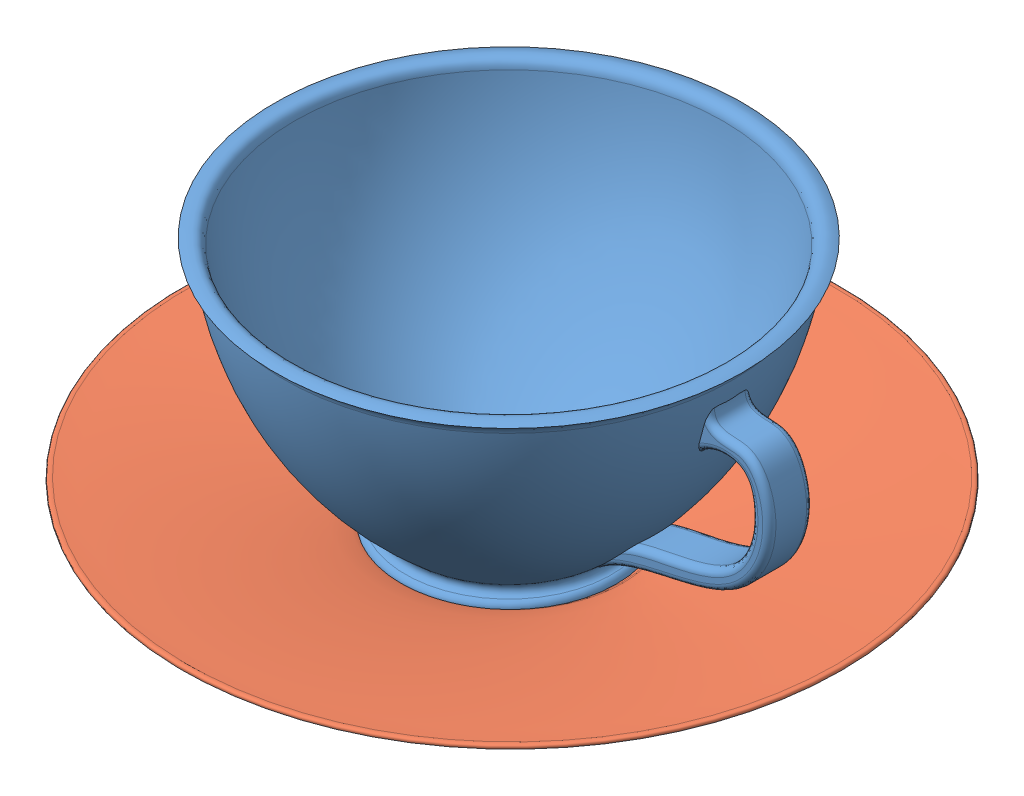
SolidWorks assembly Assingment4_Chen, configuration Default. Lengths in mm.
Overall size (150.23 62.87 150.23).
2 component instances, 2 part files, 2 mates.
Components (placement in the parent):
- TeaCup-1: TeaCup [Default] at (26.927 50.174 118.5205) size (126.46 62.44 106.43)
- Saucer-1: Saucer [Default] at (26.8771 48.674 117.703) size (150.23 13.01 150.23)
Mates (geometry in assembly coordinates):
- Coincident2: coincident anti-aligned: plane of TeaCup-1 through (26.927 48.674 118.5205) normal (0 -1 0); plane of Saucer-1 through (26.8771 48.674 117.703) normal (0 1 0)
- Parallel1: parallel anti-aligned: plane of TeaCup-1 through (26.927 52.674 118.5205) normal (0 1 0); plane of Saucer-1 through (26.8771 45.2977 117.703) normal (0 -1 0)
